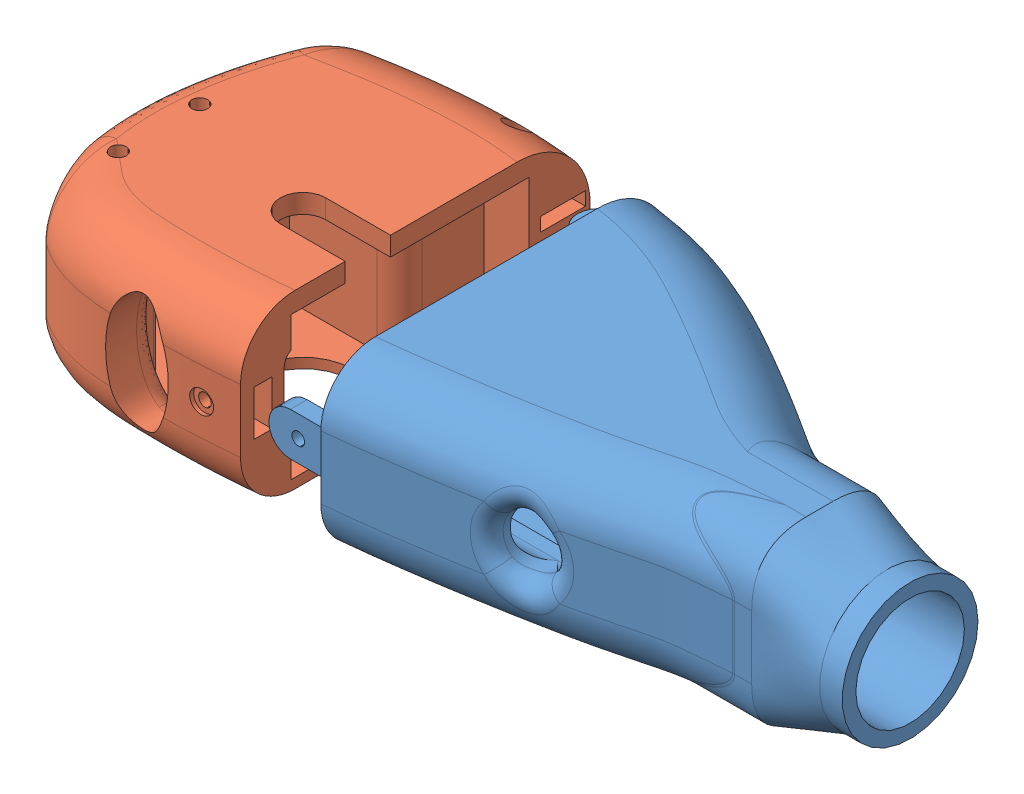
SolidWorks assembly Upper Arm Assembly V1, configuration Default. Lengths in mm.
Overall size (176.55 47.82 95.46).
3 component instances, 3 part files, 3 mates.
Components (placement in the parent):
- Upper Arm Front V2-1: Upper Arm Front V2 [Default] at (-8.6101 76.4891 87.2135) size (116.57 47.82 95.46)
- Part1^Upper Arm Assembly V1-1: Part1^Upper Arm Assembly V1 [Default] at origin (virtual)
- Upper Arm Back V2-1: Upper Arm Back V2 [Default] at (-26.3584 76.4891 87.2135) size (56.73 40.84 85.27)
Mates (geometry in assembly coordinates):
- Parallel1: parallel anti-aligned: plane of Upper Arm Front V2-1 through (5.7268 56.0074 30.4999) normal (-1 0 0); plane of Upper Arm Back V2-1 through (-12.0215 88.4891 97.2135) normal (1 0 0)
- Concentric1: concentric aligned: circle of Upper Arm Front V2-1; circle of Upper Arm Back V2-1
- Parallel3: parallel anti-aligned: line of Upper Arm Front V2-1 through (5.7268 63.4891 51.7135) axis (0 0 1); line of Upper Arm Back V2-1 through (-12.0215 59.6891 76.2135) axis (0 0 -1)
